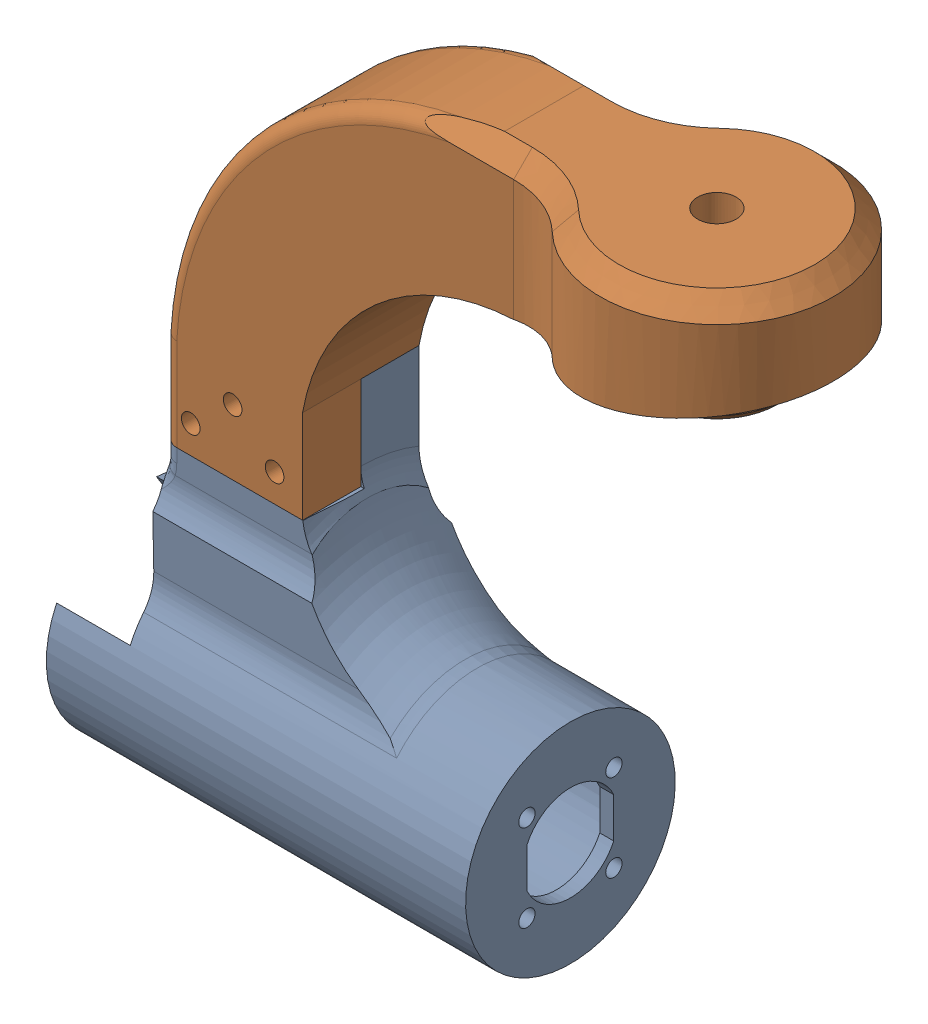
SolidWorks assembly Wheel_Steer_Assemblyleftleft11, configuration Default. Lengths in mm.
Overall size (146.44 156.21 50).
2 component instances, 2 part files, 6 mates.
Components (placement in the parent):
- Motor_holder_end_wheelsleft1-1: Motor_holder_end_wheelsleft1 [Default] at (-15 -43.7083 -12.5) x (0 1 0) z (-1 0 0) size (86.21 45 90)
- Steer_to_motor_holderleft1-1: Steer_to_motor_holderleft1 [Default] at origin size (131.61 90 50)
Mates (geometry in assembly coordinates):
- Coincident1: coincident aligned: plane of Steer_to_motor_holderleft1-1 through (0 0 0) normal (0 0 1)
- Coincident2: coincident aligned: plane of Steer_to_motor_holderleft1-1 through (0 0 0) normal (0 1 0)
- Coincident3: coincident aligned: plane of Steer_to_motor_holderleft1-1 through (0 0 0) normal (1 0 0)
- Coincident4: coincident anti-aligned: plane of Motor_holder_end_wheelsleft1-1 through (48 20 -12.5) normal (0 0 1); plane of Steer_to_motor_holderleft1-1 through (49 0 -12.5) normal (0 0 -1)
- Coincident5: coincident anti-aligned: plane of Motor_holder_end_wheelsleft1-1 through (48 20 -25) normal (0 1 0); plane of Steer_to_motor_holderleft1-1 through (49 20 -12.5) normal (0 -1 0)
- Coincident6: coincident aligned: plane of Motor_holder_end_wheelsleft1-1 through (30 -10 0) normal (1 0 0); plane of Steer_to_motor_holderleft1-1 through (30 0 -25) normal (1 0 0)
